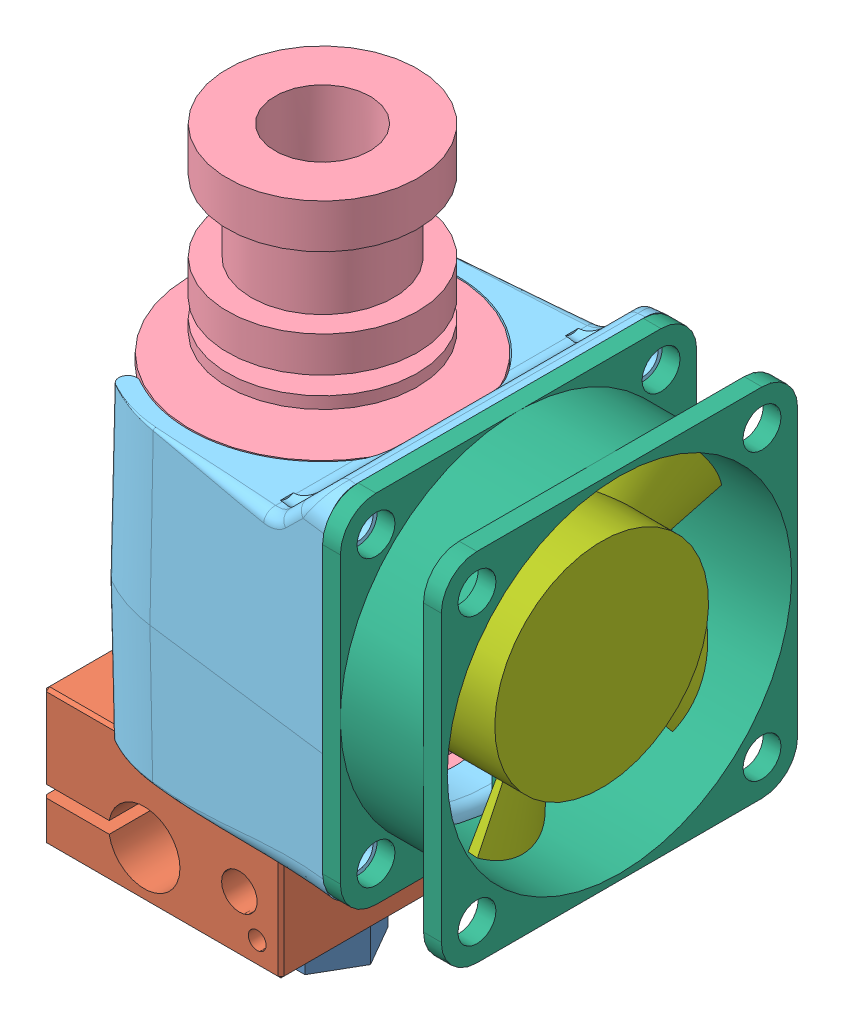
SolidWorks assembly e3d v6, configuration Default. Lengths in mm.
Overall size (40.5 61.3 39.45).
9 component instances, 7 part files, 12 mates.
Components (placement in the parent):
- e3d nozzle (0.4)-1: e3d nozzle (0.4) [Default] at (0 -4.25 0) size (8.08 12.5 7)
- e3d heaterblock-2: e3d heaterblock [Default] at (-5.5 -1.25 0) size (20 11.5 16)
- e3d heat break-2: e3d heat break [Default] at (0 5.25 0) size (7 21.9 7)
- e3d heatsink-2: e3d heatsink [Default] at (0 12.35 0) x (0.978214 0 -0.207597) z (0.207597 0 0.978214) size (22.3 42.7 22.3)
- fanduct-2: fanduct [Default] at (6.8279 9.7284 26.4875) x (-1 0 0) z (0 0 -1) size (32 39.46 39.45)
  - fan duct-1: fan duct [Default] at (6.8279 2.6216 26.4875) size (22.41 30.18 30)
  - fan-1: fan [Default] at (15.7816 1.6787 26.8895) x (0 0 1) z (-1 0 0) size (39.45 39.46 10)
    - fan sub1-1: fan sub1 [Default] at (-0.402 15.9429 23.9537) size (30 30 10)
    - fan sub2-1: fan sub2 [Default] at (-0.402 15.9429 33.9537) x (0 0 1) z (-0.65899 0.752151 0) size (8.5 27.91 28)
Mates (geometry in assembly coordinates):
- Symmetric1: symmetric aligned: plane of e3d nozzle (0.4)-1 through (-2.0207 -1.25 -3.5) normal (0 0 -1); plane of e3d nozzle (0.4)-1 through (2.0207 -1.25 3.5) normal (0 0 1); plane of assembly
- Symmetric2: symmetric aligned: line of e3d nozzle (0.4)-1 through (3 4.0415 -1.25) axis (0 0 -1); line of e3d nozzle (0.4)-1 through (3 -4.0415 -1.25) axis (0 0 -1); plane of assembly
- Symmetric3: symmetric aligned: plane of e3d nozzle (0.4)-1 through (0 6.25 0) normal (0 1 0); plane of e3d nozzle (0.4)-1 through (0 -6.25 0) normal (0 -1 0); plane of assembly
- Concentric2: concentric anti-aligned: cylinder of e3d nozzle (0.4)-1 through (0 -1.25 0) axis (0 1 0) radius 3; cylinder of e3d heaterblock-2 through (0 -1.25 0) axis (0 -1 0) radius 3
- Coincident3: coincident anti-aligned: plane of e3d nozzle (0.4)-1 through (0 -1.25 0) normal (0 1 0); plane of e3d heaterblock-2 through (-5.5 -1.25 0) normal (0 -1 0)
- Concentric3: concentric anti-aligned: cylinder of e3d heaterblock-2 through (0 -1.25 0) axis (0 -1 0) radius 3; cylinder of e3d heat break-2 through (0 5.25 0) axis (0 1 0) radius 3
- Coincident4: coincident aligned: plane of e3d heaterblock-2 through (-5.5 10.25 0) normal (0 1 0); plane of e3d heat break-2 through (1.4 10.25 0) normal (0 1 0)
- Concentric4: concentric anti-aligned: cylinder of e3d heat break-2 through (0 5.25 0) axis (0 1 0) radius 3.5; cylinder of e3d heatsink-2 through (0 55.05 0) axis (0 -1 0) radius 3.5
- Coincident5: coincident aligned: plane of e3d heat break-2 through (3.5 12.35 0) normal (0 -1 0); plane of e3d heatsink-2 through (3.4238 12.35 -0.7266) normal (0 -1 0)
- Concentric5: concentric aligned: cylinder of e3d heatsink-2 through (0 55.05 0) axis (0 -1 0) radius 11.15; cone of fanduct-2/fan duct-1 through (0 39.714 0) axis (0 -1 0)
- Coincident6: coincident aligned: plane of e3d heatsink-2 through (10.9071 38.35 -2.3147) normal (0 1 0); plane of fanduct-2/fan duct-1 through (6.9058 38.35 -0.792) normal (0 1 0)
- Parallel1: parallel aligned: plane of e3d heaterblock-2 through (4.5 10.25 8) normal (0 0 1); plane of fanduct-2/fan-1/fan sub1-1 through (15 42.35 15) normal (0 0 1)
